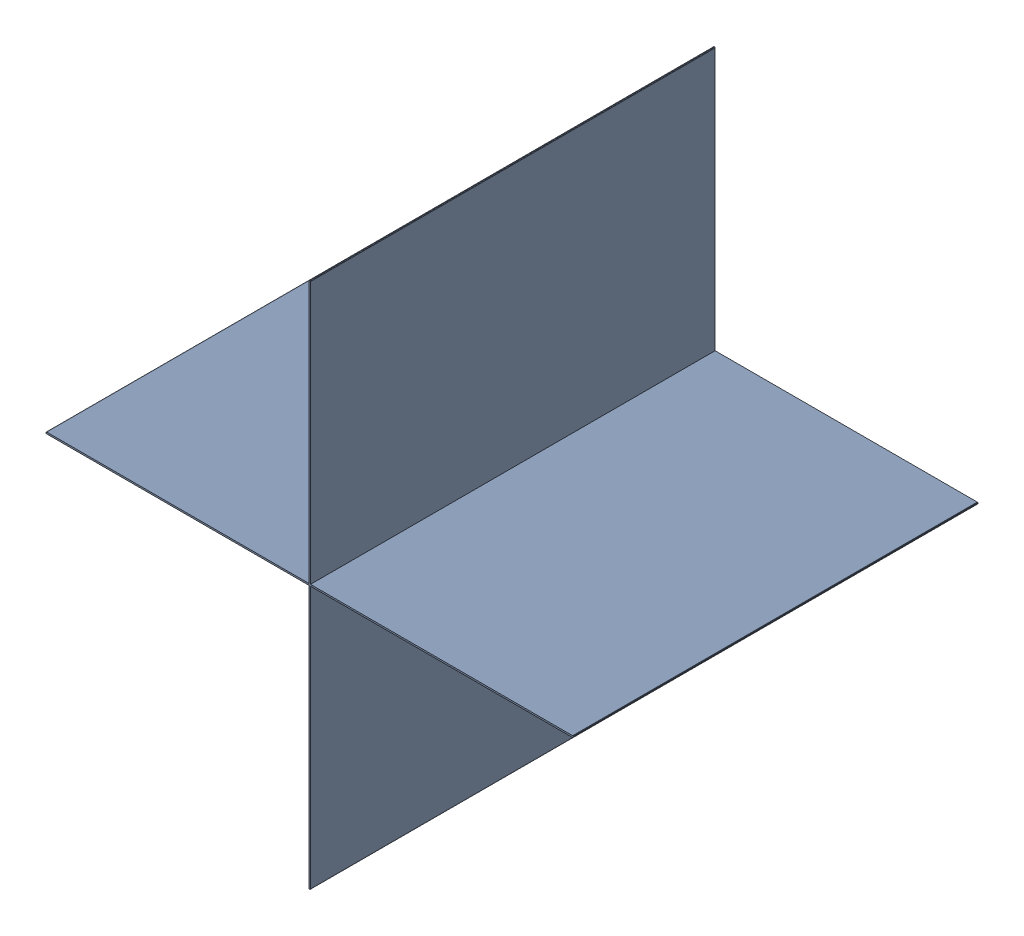
SolidWorks assembly 6327400768, configuration Default. Lengths in mm.
Overall size (0.33 0.33 0.25).
2 component instances, 1 part files, 0 mates.
Components (placement in the parent):
- 6701982208-1:  [Default] at (27.7 14.8 0) (suppressed, hidden)
- Extruded-6-1: Extruded-6 [Default] at origin size (0.33 0.33 0.25)
